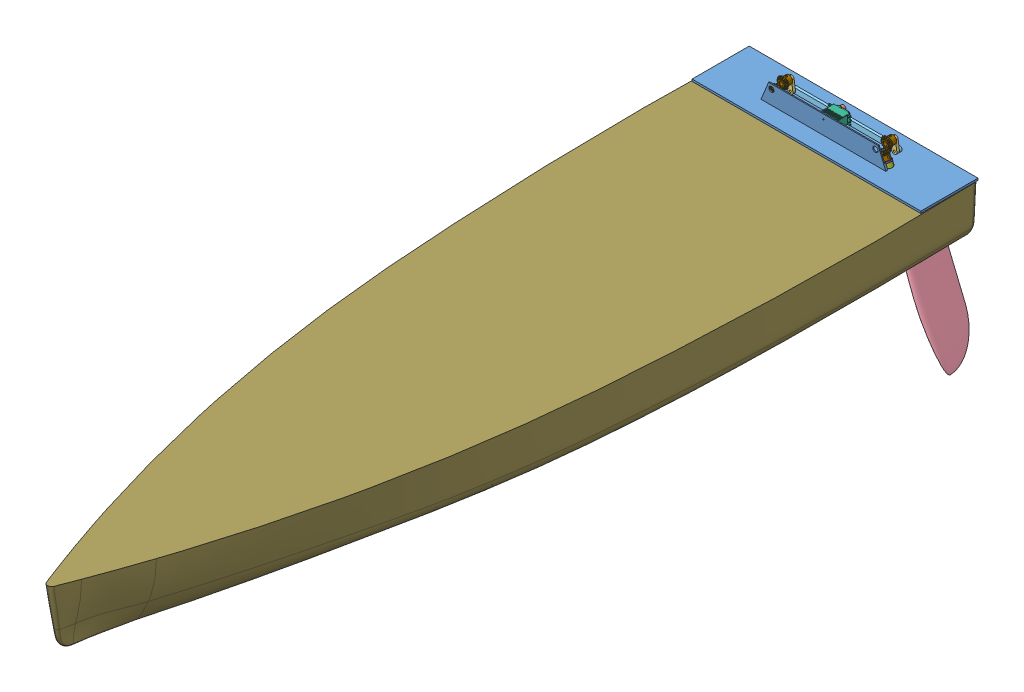
SolidWorks assembly TwinRudderGeared, configuration Default. Lengths in mm.
Overall size (604.98 418.7 2000.22).
26 component instances, 12 part files, 87 mates.
Components (placement in the parent):
- GearedRudderDeck-1: GearedRudderDeck [Default] at (2.3259 -15.0275 70.4463) size (558.8 50.27 139.7)
- RudderServoHorn-1: RudderServoHorn [Default] at (2.3259 23.8306 49.7453) x (-0.989685 -0.143258 0) z (-0.143258 0.989685 0) size (12.7 6.35 36.7)
- RudderOutputLink-1: RudderOutputLink [Default] at (132.7641 0.0782 56.0953) x (-0.989685 -0.143258 0) z (0.143258 -0.989685 0) size (12.7 6.35 36.7)
- RudderOutputLink-2: RudderOutputLink [Default] at (-121.2359 0.0782 56.0953) x (-0.989685 -0.143258 0) z (0.143258 -0.989685 0) size (12.7 6.35 36.7)
- AssembledRudder-1: AssembledRudder [Default] at (201.0121 -149.2351 105.3713) x (0 0 -1) z (0.382683 -0.92388 0) size (103.98 13.17 228.65)
  - Rudder-1: Rudder [Default] at (-3.175 0 19.05) size (103.98 13.17 228.65)
- AssembledRudder-2: AssembledRudder [Default] at (-196.3602 -149.2351 105.3713) x (0 0 -1) z (-0.382683 -0.92388 0) size (103.98 13.17 228.65)
  - Rudder-1: Rudder [Default] at (-3.175 0 19.05) size (103.98 13.17 228.65)
- GearedRudderCouplerLink-2: GearedRudderCouplerLink [Default] at (69.2641 0.0782 49.7453) x (-1 0 0) z (0 -1 0) size (139.7 6.35 12.7)
- GearedRudderCouplerLink-3: GearedRudderCouplerLink [Default] at (-57.7359 0.0782 43.3953) x (1 0 0) z (0 -1 0) size (139.7 6.35 12.7)
- small rudder servo-1: small rudder servo [Default] at (-7.9241 34.0806 96.6653) x (1 0 0) z (0 1 0) size (61.75 42.9 20.5)
- GearedRudderTube-1: GearedRudderTube [Default] at (206.4797 -162.435 83.1463) x (0.616642 0.255421 -0.744656) z (0.687973 0.284968 0.667448) size (21.34 171.45 21.34)
- GearedRudderTube-2: GearedRudderTube [Default] at (-201.8278 -162.435 83.1463) x (-0.027118 0.011233 0.999569) z (-0.923481 0.382519 -0.029353) size (21.34 171.45 21.34)
- 6362K215_WATER-RESISTANT DRY-RUNNING SLEEVE BRNG-1: 6362K215_WATER-RESISTANT DRY-RUNNING SLEEVE BRNG [6362K215] at (139.6536 -1.1026 83.1463) x (-0.773443 -0.320371 -0.546944) z (-0.50531 -0.209306 0.837169) size (22.23 12.7 22.23)
- 6362K215_WATER-RESISTANT DRY-RUNNING SLEEVE BRNG-2: 6362K215_WATER-RESISTANT DRY-RUNNING SLEEVE BRNG [6362K215] at (-203.0429 -165.3684 83.1463) x (0.92388 -0.382683 0) z (0 0 1) size (22.23 12.7 22.23)
- 6362K215_WATER-RESISTANT DRY-RUNNING SLEEVE BRNG-3: 6362K215_WATER-RESISTANT DRY-RUNNING SLEEVE BRNG [6362K215] at (-135.0017 -1.1026 83.1463) x (0.773443 -0.320371 0.546944) z (0.50531 -0.209306 -0.837169) size (22.23 12.7 22.23)
- 6362K215_WATER-RESISTANT DRY-RUNNING SLEEVE BRNG-4: 6362K215_WATER-RESISTANT DRY-RUNNING SLEEVE BRNG [6362K215] at (207.6947 -165.3684 83.1463) x (0.92388 0.382683 0) z (0 0 1) size (22.23 12.7 22.23)
- 7297K180_PLASTIC GEAR FOR 90 DEG MOTION TRANSFER-1: 7297K180_PLASTIC GEAR FOR 90 DEG MOTION TRANSFER [7297K18] at (129.3259 23.8306 65.6203) x (-0.99972 -0.02367 0) z (-0.02367 0.99972 0) size (27.72 19.13 27.72)
- 7297K180_PLASTIC GEAR FOR 90 DEG MOTION TRANSFER-2: 7297K180_PLASTIC GEAR FOR 90 DEG MOTION TRANSFER [7297K18] at (136.0085 7.6974 83.1463) x (0 0 1) z (-0.92388 -0.382683 0) size (27.72 19.13 27.72)
- 7297K180_PLASTIC GEAR FOR 90 DEG MOTION TRANSFER-3: 7297K180_PLASTIC GEAR FOR 90 DEG MOTION TRANSFER [7297K18] at (-124.6741 23.8306 65.6203) x (-0.999678 0.02536 0) z (0.02536 0.999678 0) size (27.72 19.13 27.72)
- 7297K180_PLASTIC GEAR FOR 90 DEG MOTION TRANSFER-4: 7297K180_PLASTIC GEAR FOR 90 DEG MOTION TRANSFER [7297K18] at (-131.3567 7.6974 83.1463) x (0 0 -1) z (0.92388 -0.382683 0) size (27.72 19.13 27.72)
- GearedRudderShaft-1: GearedRudderShaft [Default] at (213.1623 -178.5683 83.1463) x (-0.92388 -0.382683 0) z (0 0 -1) size (9.53 211.14 9.53)
- GearedRudderShaft-2: GearedRudderShaft [Default] at (-208.5104 -178.5683 83.1463) x (-0.92388 0.382683 0) z (0 0 -1) size (9.53 211.14 9.53)
- RudderDrivePlate-1: RudderDrivePlate [Default] at (213.4661 -179.3016 79.9713) x (0 0 -1) z (0.92388 0.382683 0) size (25.4 23.81 3.17)
- RudderDrivePlate-2: RudderDrivePlate [Default] at (-208.8142 -179.3016 79.9713) x (0 0 -1) z (0.92388 -0.382683 0) size (25.4 23.81 3.17)
- Hull 9-1: Hull 9 [Default] at (2.5961 -15.0275 0.5963) size (596.04 203.22 2000.22)
Mates (geometry in assembly coordinates):
- Concentric124: concentric aligned: cylinder of ? through (88.9494 -69.6283 82.55) axis (0.382683 -0.92388 0) radius 9.525; cylinder of ? through (83.1173 -55.5484 82.55) axis (0.382683 -0.92388 0) radius 5.5563
- Concentric125: concentric aligned: cylinder of ? through (85.8684 -62.6566 72.5186) axis (0.016434 0.006807 0.999842) radius 1.5602; cylinder of ? through (86.1246 -62.5505 88.1054) axis (0.016434 0.006807 0.999842) radius 1.524
- Concentric126: concentric aligned: cylinder of ? through (-88.9494 -69.6283 82.55) axis (-0.382683 -0.92388 0) radius 9.525; cylinder of ? through (-83.1173 -55.5484 82.55) axis (-0.382683 -0.92388 0) radius 5.5563
- Concentric127: concentric aligned: cylinder of ? through (-85.8684 -62.6566 92.5814) axis (-0.016434 0.006807 -0.999842) radius 1.5602; cylinder of ? through (-86.1246 -62.5505 76.9946) axis (-0.016434 0.006807 -0.999842) radius 1.524
- Concentric130: concentric anti-aligned: cylinder of ? through (125.886 -158.8011 82.55) axis (-0.382683 0.92388 0) radius 5.5563; cylinder of ? through (83.1173 -55.5484 82.55) axis (0.382683 -0.92388 0) radius 5.5563
- Concentric131: concentric aligned: cylinder of ? through (123.8212 -152.7832 104.7715) axis (0.016434 0.006807 0.999842) radius 2.1526; cylinder of ? through (123.5472 -152.8967 88.1054) axis (0.016434 0.006807 0.999842) radius 1.524
- Concentric132: concentric anti-aligned: cylinder of ? through (-83.1173 -55.5484 82.55) axis (-0.382683 -0.92388 0) radius 5.5563; cylinder of ? through (-125.886 -158.8011 82.55) axis (0.382683 0.92388 0) radius 5.5563
- Concentric133: concentric anti-aligned: cylinder of ? through (-123.5472 -152.8967 76.9946) axis (-0.016434 0.006807 -0.999842) radius 1.524; cylinder of ? through (-123.0907 -153.0858 104.7715) axis (0.016434 -0.006807 0.999842) radius 2.1526
- Concentric134: concentric aligned: cylinder of ? through (79.375 26.7653 82.55) axis (0 -1 0) radius 5.5563; cylinder of RudderOutputLink-1 through (79.375 25.1777 82.55) axis (0 -1 0) radius 9.525
- Concentric135: concentric anti-aligned: cylinder of ? through (73.8198 22.0028 82.657) axis (-0.999815 0 0.019253) radius 1.524; cylinder of RudderOutputLink-1 through (88.8982 22.0028 82.3666) axis (0.999815 0 -0.019253) radius 1.8288
- Concentric136: concentric aligned: cylinder of ? through (-79.375 26.7653 82.55) axis (0 -1 0) radius 5.5563; cylinder of RudderOutputLink-2 through (-79.375 25.1777 82.55) axis (0 -1 0) radius 9.525
- Concentric137: concentric aligned: cylinder of ? through (-73.8198 22.0028 82.443) axis (0.999815 0 -0.019253) radius 1.524; cylinder of RudderOutputLink-2 through (-69.8518 22.0028 82.3666) axis (0.999815 0 -0.019253) radius 1.8288
- Concentric139: concentric aligned: circle of RudderOutputLink-1; cylinder of GearedRudderCouplerLink-2 through (132.7641 0.0782 43.3953) axis (0 0 -1) radius 2.3813
- Coincident56: coincident anti-aligned: plane of GearedRudderDeck-1 through (0 5.08 69.85) normal (0 1 0); plane of ? through (20.5008 5.08 69.55) normal (0 -1 0)
- Coincident57: coincident anti-aligned: plane of GearedRudderDeck-1 through (14.0008 0 67.55) normal (0 0 1); plane of ? through (-58.4992 10.08 67.55) normal (0 0 -1)
- Coincident59: coincident anti-aligned: plane of GearedRudderDeck-1 through (14.0008 0 67.55) normal (-1 0 0); plane of ? through (14.0008 -35.92 97.05) normal (1 0 0)
- Coincident60: coincident aligned: line of GearedRudderDeck-1 through (-177.8 5.08 139.7) axis (1 0 0); line of ? through (-177.8 5.08 139.7) axis (1 0 0)
- Coincident61: coincident anti-aligned: line of GearedRudderDeck-1 through (177.8 5.08 139.7) axis (0 0 -1); line of ? through (177.8 5.08 139.7) axis (0 0 1)
- Concentric146: concentric aligned: cylinder of RudderServoHorn-1 through (0.0008 31.5278 82.55) axis (0 1 0) radius 3.175; circle of ?
- Coincident65: coincident anti-aligned: circle of GearedRudderCouplerLink-2; circle of GearedRudderCouplerLink-3
- Concentric147: concentric anti-aligned: cylinder of RudderOutputLink-2 through (-121.2359 0.0782 49.7453) axis (0 0 -1) radius 2.3813; cylinder of GearedRudderCouplerLink-3 through (-121.2359 0.0782 49.7453) axis (0 0 1) radius 2.3813
- Concentric148: concentric aligned: cylinder of RudderServoHorn-1 through (5.7641 0.0782 56.0953) axis (0 0 1) radius 2.0193; cylinder of GearedRudderCouplerLink-3 through (5.7641 0.0782 49.7453) axis (0 0 1) radius 2.0193
- Concentric150: concentric aligned: cylinder of RudderServoHorn-1 through (2.3259 23.8306 56.0953) axis (0 0 -1) radius 3.175; circle of small rudder servo-1
- Coincident70: coincident anti-aligned: plane of RudderServoHorn-1 through (5.7641 0.0782 49.7453) normal (0 0 -1); plane of GearedRudderCouplerLink-2 through (132.7641 0.0782 49.7453) normal (0 0 1)
- Coincident71: coincident anti-aligned: plane of small rudder servo-1; plane of ? through (9.875 22.6421 104.8) normal (0 1 0)
- Concentric151: concentric aligned: cylinder of small rudder servo-1 through (-15.175 22.7421 77.3) axis (0 1 0) radius 2.25; cylinder of ? through (-15.175 22.6421 77.3) axis (0 1 0) radius 1.1906
- Concentric152: concentric aligned: cylinder of small rudder servo-1 through (34.925 22.7421 77.3) axis (0 1 0) radius 2.25; cylinder of ? through (34.925 22.6421 77.3) axis (0 1 0) radius 1.1906
- Coincident72: coincident aligned: line of ? through (14.6375 22.6421 99.72) axis (-1 0 0); line of ? through (14.6375 22.6421 99.72) axis (-1 0 0)
- Coincident73: coincident anti-aligned: line of ? through (14.6375 22.6421 104.8) axis (0 0 -1); line of ? through (14.6375 22.6421 99.72) axis (0 0 1)
- Coincident74: coincident aligned: line of ? through (39.72 22.6421 73.05) axis (0 0 1); line of ? through (39.72 22.6421 73.05) axis (0 0 1)
- Coincident75: coincident anti-aligned: line of ? through (39.72 22.6421 82.575) axis (1 0 0); line of ? through (44.8 22.6421 82.575) axis (-1 0 0)
- Coincident76: coincident anti-aligned: line of ? through (-19.97 22.6421 82.575) axis (0 0 -1); line of ? through (-19.97 22.6421 73.05) axis (0 0 1)
- Coincident77: coincident anti-aligned: line of ? through (-25.05 22.6421 82.575) axis (1 0 0); line of ? through (-19.97 22.6421 82.575) axis (-1 0 0)
- Concentric153: concentric aligned: cylinder of GearedRudderDeck-1 through (102.8166 -25.4 82.55) axis (-0.382683 0.92388 0) radius 10.668; cylinder of ? through (152.1387 -144.4742 82.55) axis (-0.382683 0.92388 0) radius 5.5563
- Concentric154: concentric anti-aligned: cylinder of GearedRudderDeck-1 through (10.8798 249.0874 82.55) axis (-0.382683 -0.92388 0) radius 10.668; cylinder of ? through (-152.1387 -144.4742 82.55) axis (0.382683 0.92388 0) radius 5.5563
- Concentric155: concentric anti-aligned: circle of GearedRudderTube-1; circle of 6362K215_WATER-RESISTANT DRY-RUNNING SLEEVE BRNG-1
- Coincident78: coincident anti-aligned: plane of GearedRudderTube-1 through (140.8686 -4.0359 83.1463) normal (-0.382683 0.92388 0); circle of 6362K215_WATER-RESISTANT DRY-RUNNING SLEEVE BRNG-1
- Concentric157: concentric aligned: cylinder of GearedRudderTube-1 through (140.8686 -4.0359 83.1463) axis (0.382683 -0.92388 0) radius 10.668; cylinder of 6362K215_WATER-RESISTANT DRY-RUNNING SLEEVE BRNG-4 through (202.8346 -153.6351 83.1463) axis (0.382683 -0.92388 0) radius 7.9375
- Coincident79: coincident aligned: circle of GearedRudderTube-1; plane of 6362K215_WATER-RESISTANT DRY-RUNNING SLEEVE BRNG-4 through (206.4797 -162.435 83.1463) normal (-0.382683 0.92388 0)
- Concentric158: concentric anti-aligned: circle of GearedRudderTube-2; circle of 6362K215_WATER-RESISTANT DRY-RUNNING SLEEVE BRNG-3
- Coincident80: coincident anti-aligned: plane of GearedRudderTube-2 through (-136.2168 -4.0359 83.1463) normal (0.382683 0.92388 0); plane of 6362K215_WATER-RESISTANT DRY-RUNNING SLEEVE BRNG-3 through (-136.2168 -4.0359 83.1463) normal (-0.382683 -0.92388 0)
- Concentric159: concentric aligned: cylinder of GearedRudderTube-2 through (-136.2168 -4.0359 83.1463) axis (-0.382683 -0.92388 0) radius 10.668; cylinder of 6362K215_WATER-RESISTANT DRY-RUNNING SLEEVE BRNG-2 through (-198.1828 -153.6351 83.1463) axis (-0.382683 -0.92388 0) radius 7.9375
- Coincident81: coincident aligned: circle of GearedRudderTube-2; plane of 6362K215_WATER-RESISTANT DRY-RUNNING SLEEVE BRNG-2 through (-201.8278 -162.435 83.1463) normal (0.382683 0.92388 0)
- Concentric160: concentric aligned: cylinder of GearedRudderDeck-1 through (13.2057 356.7019 83.1463) axis (-0.382683 -0.92388 0) radius 10.668; cylinder of GearedRudderTube-2 through (-136.2168 -4.0359 83.1463) axis (-0.382683 -0.92388 0) radius 10.668
- Coincident82: coincident anti-aligned: plane of ? through (-147.5202 -132.6408 104.7735) normal (0.382683 0.92388 0); plane of 6362K215_WATER-RESISTANT DRY-RUNNING SLEEVE BRNG-2 through (-147.2787 -132.7409 82.55) normal (-0.382683 -0.92388 0)
- Coincident83: coincident anti-aligned: plane of ? through (147.6439 -132.5896 104.7715) normal (-0.382683 0.92388 0); plane of 6362K215_WATER-RESISTANT DRY-RUNNING SLEEVE BRNG-4 through (147.2787 -132.7409 82.55) normal (0.382683 -0.92388 0)
- Concentric161: concentric anti-aligned: cylinder of GearedRudderDeck-1 through (155.9425 -40.4275 83.1463) axis (-0.382683 0.92388 0) radius 10.668; cylinder of GearedRudderTube-1 through (140.8686 -4.0359 83.1463) axis (0.382683 -0.92388 0) radius 10.668
- Coincident84: coincident aligned: plane of GearedRudderDeck-1 through (149.5095 2.9799 98.8943) normal (-0.382683 0.92388 0); plane of 6362K215_WATER-RESISTANT DRY-RUNNING SLEEVE BRNG-1 through (139.6536 -1.1026 83.1463) normal (-0.382683 0.92388 0)
- Coincident85: coincident aligned: plane of GearedRudderDeck-1 through (-144.8577 2.9799 98.8943) normal (0.382683 0.92388 0); plane of 6362K215_WATER-RESISTANT DRY-RUNNING SLEEVE BRNG-3 through (-135.0017 -1.1026 83.1463) normal (0.382683 0.92388 0)
- Concentric162: concentric aligned: cylinder of GearedRudderTube-2 through (-136.2168 -4.0359 83.1463) axis (-0.382683 -0.92388 0) radius 10.668; cylinder of 7297K180_PLASTIC GEAR FOR 90 DEG MOTION TRANSFER-4 through (-127.3471 17.3773 83.1463) axis (-0.382683 -0.92388 0) radius 4.7625
- Coincident86: coincident anti-aligned: plane of 6362K215_WATER-RESISTANT DRY-RUNNING SLEEVE BRNG-3 through (-135.0017 -1.1026 83.1463) normal (0.382683 0.92388 0); plane of 7297K180_PLASTIC GEAR FOR 90 DEG MOTION TRANSFER-4 through (-135.0017 -1.1026 83.1463) normal (-0.382683 -0.92388 0)
- Coincident87: coincident anti-aligned: plane of 6362K215_WATER-RESISTANT DRY-RUNNING SLEEVE BRNG-1 through (139.6536 -1.1026 83.1463) normal (-0.382683 0.92388 0); plane of 7297K180_PLASTIC GEAR FOR 90 DEG MOTION TRANSFER-2 through (139.6536 -1.1026 83.1463) normal (0.382683 -0.92388 0)
- Concentric163: concentric anti-aligned: cylinder of GearedRudderTube-1 through (140.8686 -4.0359 83.1463) axis (0.382683 -0.92388 0) radius 10.668; cylinder of 7297K180_PLASTIC GEAR FOR 90 DEG MOTION TRANSFER-2 through (140.0181 -1.9826 83.1463) axis (-0.382683 0.92388 0) radius 9.525
- Concentric164: concentric aligned: cylinder of GearedRudderDeck-1 through (129.3259 23.8306 96.3543) axis (0 0 1) radius 6.35; cylinder of 7297K180_PLASTIC GEAR FOR 90 DEG MOTION TRANSFER-1 through (129.3259 23.8306 55.1428) axis (0 0 1) radius 9.525
- Concentric165: concentric aligned: cylinder of GearedRudderDeck-1 through (-124.6741 23.8306 96.3543) axis (0 0 1) radius 6.35; cylinder of 7297K180_PLASTIC GEAR FOR 90 DEG MOTION TRANSFER-3 through (-124.6741 23.8306 55.1428) axis (0 0 1) radius 9.525
- Distance5: distance = 21.209 mm anti-aligned: plane of GearedRudderDeck-1 through (2.3259 -15.0275 96.3543) normal (0 0 -1); plane of 7297K180_PLASTIC GEAR FOR 90 DEG MOTION TRANSFER-3 through (-124.6741 23.8306 75.1453) normal (0 0 1)
- Coincident89: coincident aligned: plane of 7297K180_PLASTIC GEAR FOR 90 DEG MOTION TRANSFER-1 through (129.3259 23.8306 56.0953) normal (0 0 -1); plane of 7297K180_PLASTIC GEAR FOR 90 DEG MOTION TRANSFER-3 through (-124.6741 23.8306 56.0953) normal (0 0 -1)
- Concentric169: concentric anti-aligned: cylinder of RudderOutputLink-1 through (129.3259 23.8306 49.7453) axis (0 0 1) radius 4.7625; cylinder of 7297K180_PLASTIC GEAR FOR 90 DEG MOTION TRANSFER-1 through (129.3259 23.8306 76.0978) axis (0 0 -1) radius 4.7625
- Concentric170: concentric anti-aligned: cylinder of RudderOutputLink-2 through (-124.6741 23.8306 49.7453) axis (0 0 1) radius 4.7625; cylinder of 7297K180_PLASTIC GEAR FOR 90 DEG MOTION TRANSFER-3 through (-124.6741 23.8306 76.0978) axis (0 0 -1) radius 4.7625
- Coincident90: coincident anti-aligned: plane of RudderOutputLink-1 through (129.3259 23.8306 56.0953) normal (0 0 1); plane of 7297K180_PLASTIC GEAR FOR 90 DEG MOTION TRANSFER-1 through (129.3259 23.8306 56.0953) normal (0 0 -1)
- Coincident91: coincident anti-aligned: plane of RudderOutputLink-2 through (-124.6741 23.8306 56.0953) normal (0 0 1); plane of 7297K180_PLASTIC GEAR FOR 90 DEG MOTION TRANSFER-3 through (-124.6741 23.8306 56.0953) normal (0 0 -1)
- Concentric171: concentric aligned: cylinder of GearedRudderDeck-1 through (2.3259 23.8306 96.3543) axis (0 0 1) radius 1.5875; cylinder of small rudder servo-1 through (2.3259 23.8306 57.8653) axis (0 0 1) radius 6.725
- Distance6: distance = 1.27 mm anti-aligned: plane of small rudder servo-1 through (2.3259 23.8306 57.3653) normal (0 0 -1); plane of RudderServoHorn-1 through (5.7641 0.0782 56.0953) normal (0 0 1)
- Perpendicular2: perpendicular: plane of GearedRudderDeck-1 through (2.3259 -9.9475 70.4463) normal (0 1 0); plane of small rudder servo-1 through (-7.9241 34.0806 62.8653) normal (-1 0 0)
- Coincident92: coincident anti-aligned: plane of RudderOutputLink-1 through (129.3259 23.8306 49.7453) normal (0 0 -1); plane of GearedRudderCouplerLink-2 through (132.7641 0.0782 49.7453) normal (0 0 1)
- Concentric172: concentric aligned: cylinder of GearedRudderTube-1 through (140.8686 -4.0359 83.1463) axis (0.382683 -0.92388 0) radius 10.668; cylinder of GearedRudderShaft-1 through (132.3635 16.4973 83.1463) axis (0.382683 -0.92388 0) radius 4.7625
- Coincident93: coincident aligned: plane of 7297K180_PLASTIC GEAR FOR 90 DEG MOTION TRANSFER-2 through (132.3635 16.4973 83.1463) normal (-0.382683 0.92388 0); plane of GearedRudderShaft-1 through (132.3635 16.4973 83.1463) normal (-0.382683 0.92388 0)
- Concentric173: concentric aligned: cylinder of GearedRudderTube-2 through (-136.2168 -4.0359 83.1463) axis (-0.382683 -0.92388 0) radius 10.668; cylinder of GearedRudderShaft-2 through (-127.7116 16.4973 83.1463) axis (-0.382683 -0.92388 0) radius 4.7625
- Coincident94: coincident aligned: plane of 7297K180_PLASTIC GEAR FOR 90 DEG MOTION TRANSFER-4 through (-127.7116 16.4973 83.1463) normal (0.382683 0.92388 0); plane of GearedRudderShaft-2 through (-127.7116 16.4973 83.1463) normal (0.382683 0.92388 0)
- Coincident95: coincident anti-aligned: line of AssembledRudder-2/Rudder-1 through (-209.9771 -177.9608 87.6365) axis (0 0 -1); line of GearedRudderShaft-2 through (-209.9771 -177.9608 78.6562) axis (0 0 1)
- Concentric174: concentric anti-aligned: cylinder of AssembledRudder-2/Rudder-1 through (-208.5104 -178.5683 83.1463) axis (0.382683 0.92388 0) radius 4.7625; cylinder of GearedRudderShaft-2 through (-127.7116 16.4973 83.1463) axis (-0.382683 -0.92388 0) radius 4.7625
- Coincident96: coincident anti-aligned: line of AssembledRudder-1/Rudder-1 through (211.6956 -179.1758 87.6365) axis (0 0 -1); line of GearedRudderShaft-1 through (211.6956 -179.1758 78.6562) axis (0 0 1)
- Concentric175: concentric anti-aligned: cylinder of AssembledRudder-1/Rudder-1 through (213.1623 -178.5683 83.1463) axis (-0.382683 0.92388 0) radius 4.7625; cylinder of GearedRudderShaft-1 through (132.3635 16.4973 83.1463) axis (0.382683 -0.92388 0) radius 4.7625
- Coincident97: coincident anti-aligned: plane of AssembledRudder-1/Rudder-1 through (216.5557 -190.9091 108.5463) normal (0.92388 0.382683 0); plane of RudderDrivePlate-1 through (211.9994 -179.9091 79.9713) normal (-0.92388 -0.382683 0)
- Coincident98: coincident anti-aligned: plane of AssembledRudder-1/Rudder-1 through (218.0224 -190.3016 67.2713) normal (0 0 1); plane of RudderDrivePlate-1 through (219.489 -189.694 67.2713) normal (0 0 -1)
- Coincident99: coincident anti-aligned: plane of AssembledRudder-1/Rudder-1 through (218.0224 -190.3016 108.5463) normal (-0.382683 0.92388 0); plane of RudderDrivePlate-1 through (219.489 -189.694 67.2713) normal (0.382683 -0.92388 0)
- Coincident102: coincident anti-aligned: plane of AssembledRudder-2/Rudder-1 through (-214.8372 -189.694 108.5463) normal (0.92388 -0.382683 0); plane of RudderDrivePlate-2 through (-210.2809 -178.6941 79.9713) normal (-0.92388 0.382683 0)
- Coincident103: coincident anti-aligned: plane of AssembledRudder-2/Rudder-1 through (-213.3705 -190.3016 108.5463) normal (0.382683 0.92388 0); plane of RudderDrivePlate-2 through (-211.9039 -190.9091 67.2713) normal (-0.382683 -0.92388 0)
- Coincident104: coincident anti-aligned: plane of AssembledRudder-2/Rudder-1 through (-213.3705 -190.3016 67.2713) normal (0 0 1); plane of RudderDrivePlate-2 through (-211.9039 -190.9091 67.2713) normal (0 0 -1)
- GearMate1: gear = 19.05 : 19.05 mm: cylinder of 7297K180_PLASTIC GEAR FOR 90 DEG MOTION TRANSFER-2 through (140.0181 -1.9826 83.1463) axis (-0.382683 0.92388 0) radius 9.525; cylinder of 7297K180_PLASTIC GEAR FOR 90 DEG MOTION TRANSFER-1 through (129.3259 23.8306 55.1428) axis (0 0 1) radius 9.525
- GearMate2: gear = 19.05 : 19.05 mm: cylinder of 7297K180_PLASTIC GEAR FOR 90 DEG MOTION TRANSFER-3 through (-124.6741 23.8306 55.1428) axis (0 0 1) radius 9.525; cylinder of 7297K180_PLASTIC GEAR FOR 90 DEG MOTION TRANSFER-4 through (-135.3662 -1.9826 83.1463) axis (0.382683 0.92388 0) radius 9.525
- Concentric176: concentric anti-aligned: cylinder of 7297K180_PLASTIC GEAR FOR 90 DEG MOTION TRANSFER-4 through (-123.7717 1.119 83.1463) axis (0.92388 -0.382683 0) radius 2.2479; cylinder of GearedRudderShaft-2 through (-136.9717 6.5866 83.1463) axis (-0.92388 0.382683 0) radius 1.7272
- Concentric177: concentric aligned: cylinder of 7297K180_PLASTIC GEAR FOR 90 DEG MOTION TRANSFER-2 through (128.4236 1.119 83.1463) axis (-0.92388 -0.382683 0) radius 2.2479; cylinder of GearedRudderShaft-1 through (132.8236 2.9415 83.1463) axis (-0.92388 -0.382683 0) radius 1.7272
- Coincident106: coincident aligned: plane of GearedRudderShaft-1 through (213.1623 -178.5683 83.1463) normal (0 0 -1); plane of GearedRudderShaft-2 through (-208.5104 -178.5683 83.1463) normal (0 0 -1)
- Coincident107: coincident aligned: line of GearedRudderDeck-1 through (281.7259 -15.0275 0.5963) axis (-1 0 0); line of Hull 9-1 through (272.7319 -15.0275 0.5963) axis (-1 0 0)
- Parallel1: parallel aligned: plane of GearedRudderDeck-1 through (281.7259 -9.9475 0.5963) normal (0 0 -1); plane of Hull 9-1 through (2.5961 -15.0275 0.5963) normal (0 0 -1)
- Coincident109: coincident: line of GearedRudderDeck-1 through (-277.0741 -15.0275 0.5963) axis (0 0 1); point of Hull 9-1
